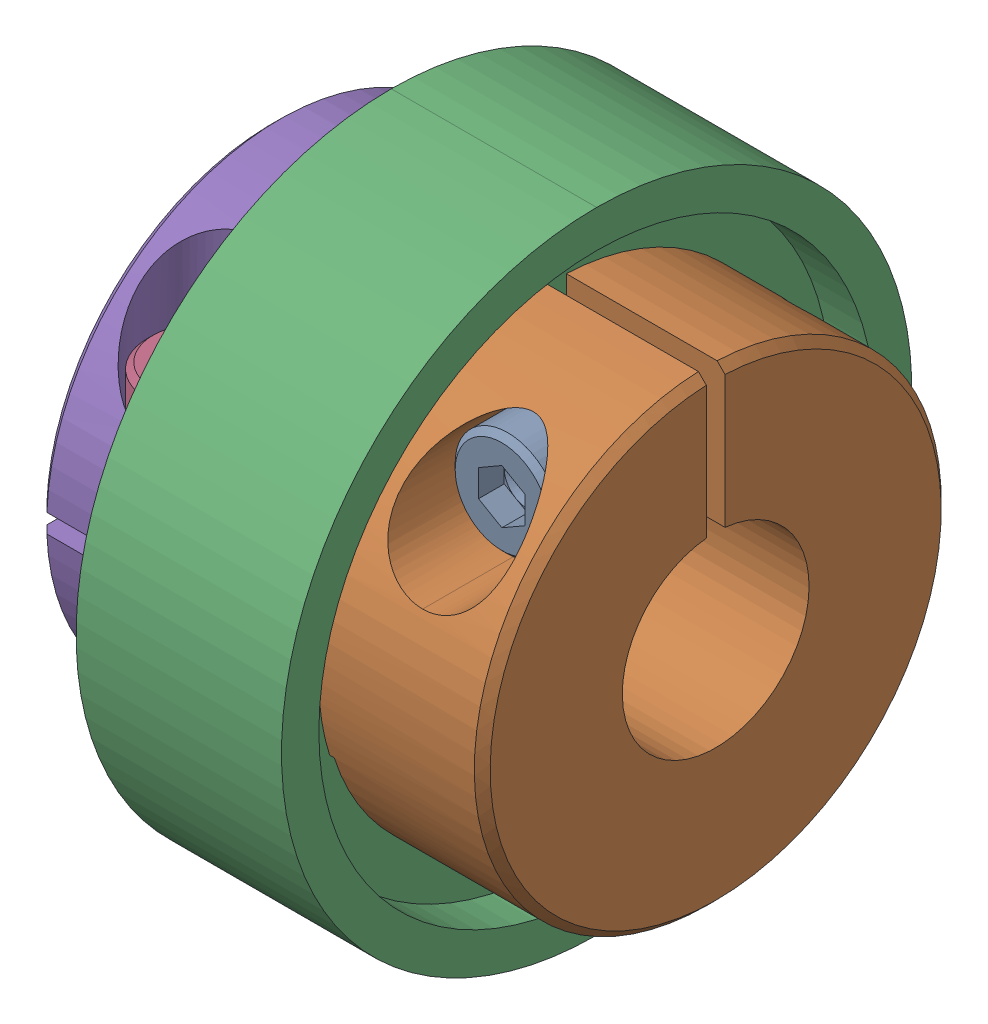
SolidWorks assembly SCOC20_6_8, configuration Default. Lengths in mm.
Overall size (19 27 27).
5 component instances, 4 part files, 0 mates.
Components (placement in the parent):
- SCOC20_6_8_3-1: SCOC20_6_8_3 [Default] at (15.6 6.5 3.4) x (0 0 -1) z (1 0 0) size (10.36 4.5 4.5)
- SCOC20_6_8_5-1: SCOC20_6_8_5 [Default] at (19 0 0) x (-1 0 0) z (0 1 0) size (10.2 20 19.99)
- SCOC20_6_8_7-1: SCOC20_6_8_7 [Default] at (19 0 0) x (-1 0 0) z (0 -1 0) size (8.8 27 27)
- SCOC20_6_8_3-2: SCOC20_6_8_3 [Default] at (3.4 3.4 6.5) x (0 -1 0) z (-1 0 0) size (10.36 4.5 4.5)
- SCOC20_6_8_10-1: SCOC20_6_8_10 [Default] at origin size (10.2 20 19.99)
